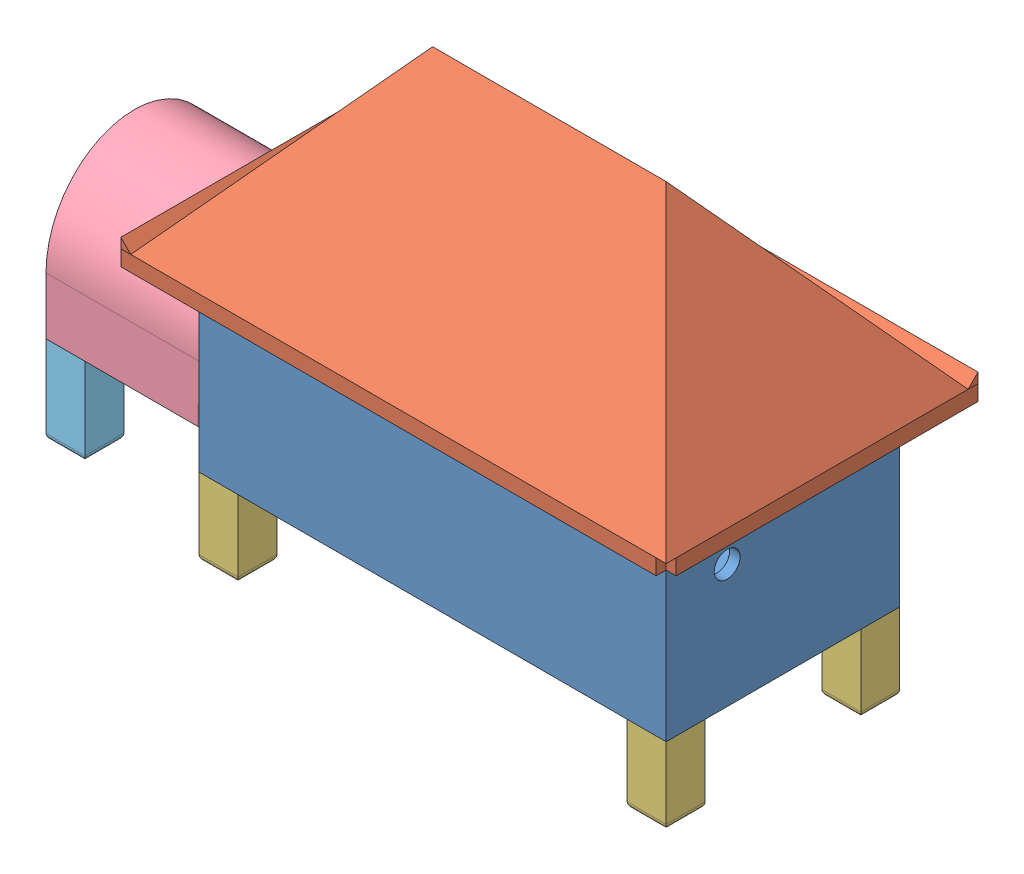
SolidWorks assembly Enclosure, configuration Default. Lengths in mm.
Overall size (267 171.97 124).
10 component instances, 5 part files, 18 mates.
Components (placement in the parent):
- Case Enclosure-1: Case Enclosure [Default] at (-23.7329 39.8836 85.4894) size (180 100 90)
- Roof Enclosure-1: Roof Enclosure [Default] at (66.2671 110.3501 70.4894) size (214 71.51 124)
- Enclosure Feet-1: Enclosure Feet [Default] at (141.2671 9.8836 175.4894) x (1 0 0) z (0 1 0) size (15 15 30)
- Enclosure Feet-2: Enclosure Feet [Default] at (141.2671 9.8836 100.4894) x (1 0 0) z (0 1 0) size (15 15 30)
- Enclosure Feet-3: Enclosure Feet [Default] at (-23.7329 9.8836 175.4894) x (1 0 0) z (0 1 0) size (15 15 30)
- Enclosure Feet-4: Enclosure Feet [Default] at (-23.7329 9.8836 100.4894) x (1 0 0) z (0 1 0) size (15 15 30)
- Assem1^Enclosure-1: Assem1^Enclosure [Default] at (-15 4 0) size (70 101.75 83) (virtual)
  - Cable Enclosure-1: Cable Enclosure [Default] at (-43.7329 50.8836 130.4894) x (0 1 0) z (0 0 -1) size (67.75 70 83)
  - Cable Enclosure Feet-1: Cable Enclosure Feet [Default] at (-78.7329 5.8836 111.4894) x (1 0 0) z (0 1 0) size (15 15 34)
  - Cable Enclosure Feet-2: Cable Enclosure Feet [Default] at (-78.7329 5.8836 164.4894) x (1 0 0) z (0 1 0) size (15 15 34)
Mates (geometry in assembly coordinates):
- Parallel1: parallel anti-aligned: plane of Case Enclosure-1 through (-23.7329 111.3536 85.4894) normal (0 1 0); plane of Roof Enclosure-1 through (171.2671 110.3501 190.4894) normal (0 -1 0)
- Coincident10: coincident aligned: line of Case Enclosure-1 through (-23.7329 122.0036 175.4894) axis (0.540716 0.6444 -0.540716); line of Roof Enclosure-1 through (-33.5113 110.3501 185.2678) axis (0.540716 0.6444 -0.540716)
- Coincident11: coincident aligned: line of Case Enclosure-1 through (156.2671 122.0036 85.4894) axis (-0.540716 0.6444 0.540716); line of Roof Enclosure-1 through (166.0454 110.3501 75.711) axis (-0.540716 0.6444 0.540716)
- Coincident12: coincident anti-aligned: plane of Case Enclosure-1 through (-23.7329 39.8836 85.4894) normal (0 -1 0); plane of Enclosure Feet-4 through (-23.7329 39.8836 100.4894) normal (0 1 0)
- Coincident13: coincident anti-aligned: plane of Case Enclosure-1 through (-23.7329 39.8836 85.4894) normal (0 -1 0); plane of Enclosure Feet-3 through (-23.7329 39.8836 175.4894) normal (0 1 0)
- Coincident14: coincident anti-aligned: plane of Case Enclosure-1 through (-23.7329 39.8836 85.4894) normal (0 -1 0); plane of Enclosure Feet-2 through (141.2671 39.8836 100.4894) normal (0 1 0)
- Coincident15: coincident anti-aligned: plane of Case Enclosure-1 through (-23.7329 39.8836 85.4894) normal (0 -1 0); plane of Enclosure Feet-1 through (141.2671 39.8836 175.4894) normal (0 1 0)
- Concentric2: concentric aligned: cylinder of Case Enclosure-1 through (-16.2329 39.8836 92.9894) axis (0 -1 0) radius 1.25; cylinder of Enclosure Feet-4 through (-16.2329 9.8836 92.9894) axis (0 -1 0) radius 1.5
- Coincident16: coincident aligned: plane of Case Enclosure-1 through (-23.7329 111.3536 85.4894) normal (-1 0 0); plane of Enclosure Feet-4 through (-23.7329 39.8836 100.4894) normal (-1 0 0)
- Concentric3: concentric aligned: cylinder of Case Enclosure-1 through (-16.2329 39.8836 167.9894) axis (0 -1 0) radius 1.25; cylinder of Enclosure Feet-3 through (-16.2329 9.8836 167.9894) axis (0 -1 0) radius 1.5
- Coincident17: coincident aligned: plane of Case Enclosure-1 through (-23.7329 111.3536 85.4894) normal (-1 0 0); plane of Enclosure Feet-3 through (-23.7329 39.8836 175.4894) normal (-1 0 0)
- Concentric4: concentric aligned: cylinder of Case Enclosure-1 through (148.7671 39.8836 92.9894) axis (0 -1 0) radius 1.25; cylinder of Enclosure Feet-2 through (148.7671 9.8836 92.9894) axis (0 -1 0) radius 1.5
- Coincident18: coincident aligned: plane of Case Enclosure-1 through (-23.7329 111.3536 85.4894) normal (0 0 -1); plane of Enclosure Feet-2 through (141.2671 39.8836 85.4894) normal (0 0 -1)
- Concentric5: concentric aligned: cylinder of Case Enclosure-1 through (148.7671 39.8836 167.9894) axis (0 -1 0) radius 1.25; cylinder of Enclosure Feet-1 through (148.7671 9.8836 167.9894) axis (0 -1 0) radius 1.5
- Coincident19: coincident aligned: plane of Case Enclosure-1 through (156.2671 111.3536 85.4894) normal (1 0 0); plane of Enclosure Feet-1 through (156.2671 39.8836 175.4894) normal (1 0 0)
- Coincident28: coincident anti-aligned: plane of Case Enclosure-1 through (-23.7329 111.3536 85.4894) normal (-1 0 0); plane of Assem1^Enclosure-1/Cable Enclosure-1 through (-23.7329 54.8836 130.4894) normal (1 0 0)
- Coincident29: coincident anti-aligned: line of Case Enclosure-1 through (-23.7329 47.8836 100.4894) axis (0 0 1); line of Assem1^Enclosure-1/Cable Enclosure-1 through (-23.7329 47.8836 160.4894) axis (0 0 -1)
- Coincident30: coincident anti-aligned: line of Case Enclosure-1 through (-23.7329 47.8836 160.4894) axis (0 1 0); line of Assem1^Enclosure-1/Cable Enclosure-1 through (-23.7329 65.8836 160.4894) axis (0 -1 0)
